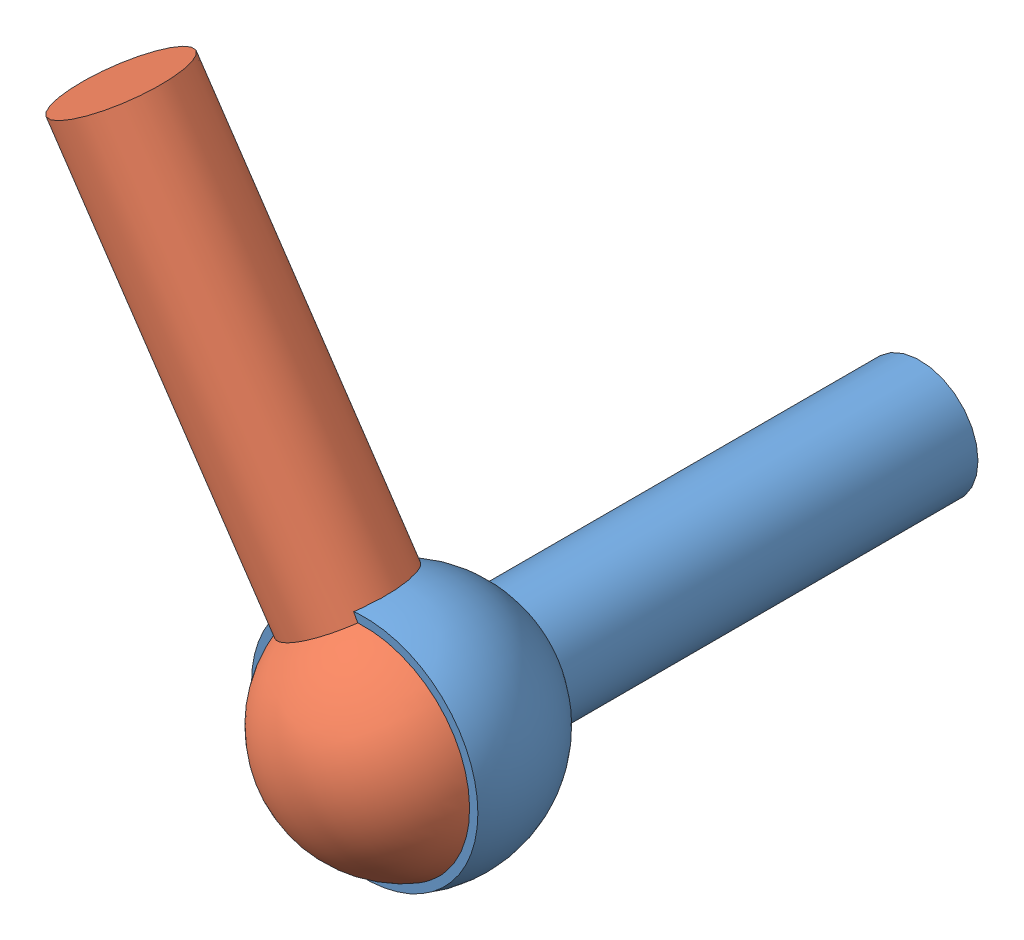
SolidWorks assembly Assem1, configuration Default. Lengths in mm.
Overall size (65.38 81.77 81.39).
2 component instances, 2 part files, 1 mates.
Components (placement in the parent):
- Part14-1: Part14 [Default] at (47.469 43.2084 75.4756) size (28.81 28.81 67)
- ball joint 11-1: ball joint 11 [Default] at (41.6353 53.1279 63.4136) x (0.845164 0.48503 0.224598) z (-0.506398 0.861069 0.046059) size (26.96 26.96 75)
Mates (geometry in assembly coordinates):
- Concentric1: concentric: sphere of Part14-1; sphere of ball joint 11-1
